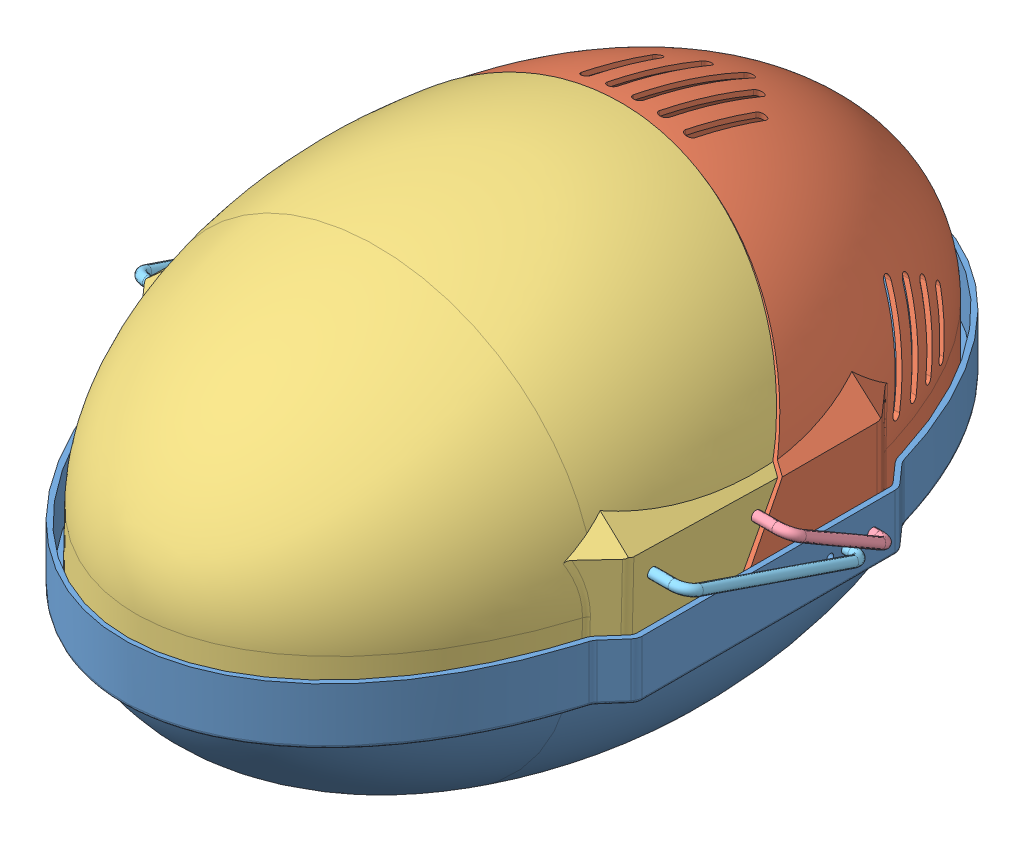
SolidWorks assembly Ensamblaje2, configuration Predeterminado. Lengths in mm.
Overall size (1079.29 607.16 1342.92).
7 component instances, 5 part files, 14 mates.
Components (placement in the parent):
- Base_fija-1: Base_fija [Predeterminado] at (-30.3348 76.8432 1.4467) size (1079.29 429.5 1342.92)
- Tapa_fija-1: Tapa_fija [Predeterminado] at (-30.3348 80.5932 1.4467) size (373.79 216.87 414.65)
- Tapa_movil-1: Tapa_movil [Predeterminado] at (-30.3348 82.3564 0.5156) x (1 0 0) z (0 0.023419 0.999726) size (382.54 306.89 468.26)
- correderachica-1: correderachica [Predeterminado] at (152.4238 102.3509 0.0472) x (0 -0.501054 -0.865416) z (-1 0 0) size (98.32 7.5 33.75)
- corredera grande-1: corredera grande [Predeterminado] at (152.4238 56.8432 -58.5533) x (0 0.323522 0.946221) z (-1 0 0) size (153.95 7.5 33.75)
- correderachica-2: correderachica [Predeterminado] at (-213.0934 56.8432 -78.5533) x (0 0.501054 0.865416) z (1 0 0) size (98.32 7.5 33.75)
- corredera grande-2: corredera grande [Predeterminado] at (-213.0934 56.8432 -58.5533) x (0 0.323522 0.946221) z (1 0 0) size (153.95 7.5 33.75)
Mates (geometry in assembly coordinates):
- Coincidente1: coincident aligned: plane of Base_fija-1 through (-30.3348 76.8432 1.4467) normal (1 0 0); plane of tapachica-1 through (-30.3348 80.5932 1.4467) normal (1 0 0)
- Coincidente3: coincident aligned: plane of Base_fija-1 through (-30.3348 76.8432 1.4467) normal (0 0 1); plane of tapachica-1 through (-30.3348 80.5932 1.4467) normal (0 0 1)
- Coincidente4: coincident anti-aligned: plane of Base_fija-1 through (-30.3348 36.8432 1.4467) normal (0 1 0); plane of tapachica-1 through (-30.3348 36.8432 1.4467) normal (0 -1 0)
- Coincidente5: coincident aligned: plane of Base_fija-1 through (-30.3348 76.8432 1.4467) normal (1 0 0); plane of Tapa_movil-1 through (-30.3348 82.3564 0.5156) normal (1 0 0)
- Concéntrica1: concentric aligned: circle of base2-1; circle of correderachica-1
- Concéntrica2: concentric aligned: circle of tapagrande-1; circle of correderachica-1
- Coincidente12: coincident aligned: circle of tapagrande-1; plane of correderachica-1 through (152.4238 102.3509 0.0472) normal (-1 0 0)
- Concéntrica3: concentric anti-aligned: circle of base2-1; circle of corredera grande-1
- Coincidente14: coincident anti-aligned: circle of tapagrande-1; circle of corredera grande-1
- Concéntrica4: concentric aligned: circle of base2-1; circle of correderachica-2
- Concéntrica5: concentric anti-aligned: circle of tapagrande-1; circle of correderachica-2
- Coincidente18: coincident anti-aligned: circle of tapagrande-1; circle of corredera grande-2
- Concéntrica6: concentric aligned: circle of base2-1; circle of corredera grande-2
- Coincidente19: coincident anti-aligned: circle of Tapa_movil-1; circle of correderachica-2
